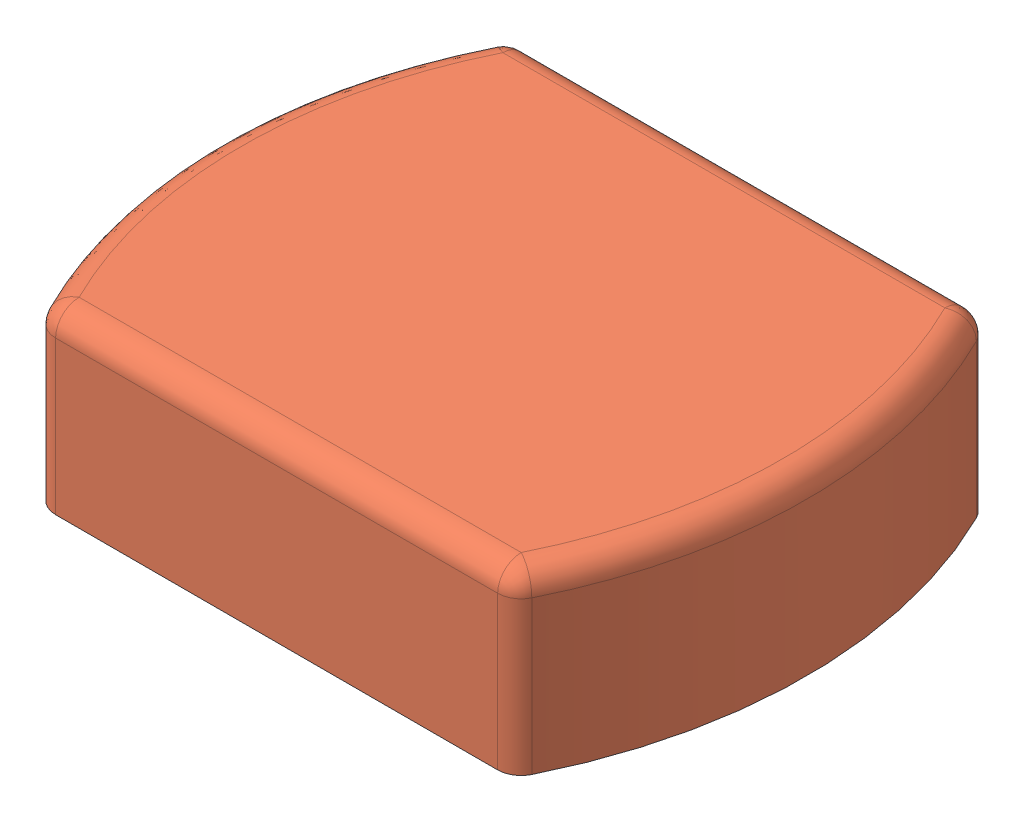
SolidWorks assembly Robot, configuration Default. Lengths in mm.
Overall size (63.5 21.87 50.8).
15 component instances, 9 part files, 28 mates.
Components (placement in the parent):
- Frame-1: Frame [Default] at origin size (45.72 11.65 40.64)
- Shell-1: Shell [Default] at (0 -11.049 0) size (63.5 19.05 50.8)
- PCB-1: PCB [Default] at (0 -5.588 0) size (45.72 1.52 40.64)
- BGM111-1: BGM111 [Default] at (-15.36 -6.75 0) x (1 0 0) z (0 0 -1) size (15 2 12.9)
- Stepper Motor-2: Stepper Motor [Default] at (7.6033 -3.826 -7.438) x (0 0 -1) z (1 0 0) size (12.5 9 8)
- 4-40 Screw-1: 4-40 Screw [92220A122] at (-20.32 -1.5875 17.78) x (0 1 0) z (0 0 1) size (11.33 4.65 4.65)
- 4-40 Screw-2: 4-40 Screw [92220A122] at (20.32 -1.5875 17.78) x (0 1 0) z (0 0 1) size (11.33 4.65 4.65)
- 4-40 Screw-3: 4-40 Screw [92220A122] at (20.32 -1.5875 -17.78) x (0 1 0) z (0 0 1) size (11.33 4.65 4.65)
- 4-40 Screw-4: 4-40 Screw [92220A122] at (-20.32 -1.5875 -17.78) x (0 1 0) z (0 0 1) size (11.33 4.65 4.65)
- Small Gear-1: Small Gear [2662N27] at (7.6033 0.174 -15.438) x (0.958969 -0.283511 0) z (0 0 1) size (6.87 6.87 3.01)
- Large Gear-1: Large Gear [2662N28] at (0 -4.826 -12.438) x (-0.58701 0.80958 0) z (0 0 -1) size (12.96 12.96 7.01)
- Stepper Motor-3: Stepper Motor [Default] at (7.6033 -3.826 7.438) x (0 0 1) z (-1 0 0) size (12.5 9 8)
- Small Gear-2: Small Gear [2662N27] at (7.6033 0.174 12.438) x (0.958969 -0.283511 0) z (0 0 1) size (6.87 6.87 3.01)
- Large Gear-2: Large Gear [2662N28] at (0 -4.826 12.438) x (0.58701 -0.80958 0) z (0 0 1) size (12.96 12.96 7.01)
- Wheel-2: Wheel [Default] at (0 -4.826 -16.438) x (-0.999664 -0.025912 0) z (0 0 -1) size (16.51 16.51 4)
Mates (geometry in assembly coordinates):
- Coincident5: coincident: plane of PCB-1 through (0 -6.35 0) normal (0 -1 0); plane of BGM111-1 through (-15.36 -6.35 0) normal (0 1 0)
- Coincident6: coincident: plane of PCB-1 through (-22.86 -4.826 -20.32) normal (-1 0 0); plane of BGM111-1 through (-22.86 -7.15 6.45) normal (-1 0 0)
- Width1: width: plane of PCB-1 through (-22.86 -4.826 20.32) normal (0 0 1); plane of PCB-1 through (-22.86 -4.826 -20.32) normal (0 0 -1); plane of BGM111-1 through (-22.86 -7.15 -6.45) normal (0 0 -1); plane of BGM111-1 through (-22.86 -7.15 6.45) normal (0 0 1)
- Width2: width: plane of Shell-1 through (-22.86 69.1723 -20.32) normal (0 0 1); plane of Shell-1 through (-22.86 69.1723 20.32) normal (0 0 -1); plane of PCB-1 through (-22.86 -4.826 -20.32) normal (0 0 -1); plane of PCB-1 through (-22.86 -4.826 20.32) normal (0 0 1)
- Width3: width: plane of Shell-1 through (-22.86 69.1723 20.32) normal (1 0 0); plane of Shell-1 through (22.86 69.1723 20.32) normal (-1 0 0); plane of PCB-1 through (-22.86 -4.826 -20.32) normal (-1 0 0); plane of PCB-1 through (22.86 -4.826 -20.32) normal (1 0 0)
- Coincident8: coincident: plane of PCB-1 through (0 -4.826 0) normal (0 1 0); plane of Stepper Motor-2 through (7.6033 -4.826 -7.438) normal (0 -1 0)
- Coincident10: coincident: plane of PCB-1 through (0 -6.35 0) normal (0 -1 0); plane of 4-40 Screw-1 through (-22.6441 -6.35 17.78) normal (0 1 0)
- Concentric1: concentric: cylinder of PCB-1 through (-20.32 -4.826 17.78) axis (0 1 0) radius 1.4732; cylinder of 4-40 Screw-1 through (-20.32 -6.35 17.78) axis (0 1 0) radius 2.3241
- Concentric2: concentric: cylinder of PCB-1 through (20.32 -4.826 17.78) axis (0 1 0) radius 1.4732; cylinder of 4-40 Screw-2 through (20.32 -6.35 17.78) axis (0 1 0) radius 2.3241
- Concentric3: concentric: cylinder of PCB-1 through (20.32 -4.826 -17.78) axis (0 1 0) radius 1.4732; cylinder of 4-40 Screw-3 through (20.32 -6.35 -17.78) axis (0 1 0) radius 2.3241
- Concentric4: concentric: cylinder of PCB-1 through (-20.32 -4.826 -17.78) axis (0 1 0) radius 1.4732; cylinder of 4-40 Screw-4 through (-20.32 -6.35 -17.78) axis (0 1 0) radius 2.3241
- Coincident11: coincident: plane of PCB-1 through (0 -6.35 0) normal (0 -1 0); plane of 4-40 Screw-4 through (-22.6441 -6.35 -17.78) normal (0 1 0)
- Coincident12: coincident: plane of PCB-1 through (0 -6.35 0) normal (0 -1 0); plane of 4-40 Screw-2 through (17.9959 -6.35 17.78) normal (0 1 0)
- Coincident13: coincident: plane of PCB-1 through (0 -6.35 0) normal (0 -1 0); plane of 4-40 Screw-3 through (17.9959 -6.35 -17.78) normal (0 1 0)
- Coincident14: coincident: plane of PCB-1 through (0 -4.826 0) normal (0 1 0); plane of Frame-1 through (0 -4.826 0) normal (0 -1 0)
- Width4: width: plane of Shell-1 through (-22.86 69.1723 20.32) normal (1 0 0); plane of Shell-1 through (22.86 69.1723 20.32) normal (-1 0 0); plane of Frame-1 through (-22.86 4.826 -20.32) normal (-1 0 0); plane of Frame-1 through (22.86 4.826 -20.32) normal (1 0 0)
- Width5: width: plane of Shell-1 through (-22.86 69.1723 -20.32) normal (0 0 1); plane of Shell-1 through (-22.86 69.1723 20.32) normal (0 0 -1); plane of Frame-1 through (-22.86 4.826 -20.32) normal (0 0 -1); plane of Frame-1 through (-22.86 4.826 20.32) normal (0 0 1)
- Coincident15: coordinate: point of Frame-1; point of assembly
- LimitDistance1: limit distance = 0 mm: plane of Frame-1 through (0 4.826 0) normal (0 1 0); plane of Shell-1 through (0 4.826 0) normal (0 -1 0)
- Concentric8: concentric: cylinder of Stepper Motor-2 through (7.6033 0.174 -12.938) axis (0 0 -1) radius 1.35; cylinder of Small Gear-1 through (7.6033 0.174 -15.4433) axis (0 0 1) radius 1.39
- Coincident23: coincident: plane of Stepper Motor-2 through (7.6033 0.174 -15.438) normal (0 0 -1); plane of Small Gear-1 through (8.5956 3.5304 -15.438) normal (0 0 -1)
- Concentric9: concentric: cylinder of Frame-1 through (0 -4.826 -19.438) axis (0 0 1) radius 2; cylinder of Large Gear-1 through (0 -4.826 -15.438) axis (0 0 1) radius 2
- Coincident26: coincident: plane of Frame-1 through (0 -4.826 -19.438) normal (0 0 -1); plane of Large Gear-1 through (1.6192 -3.652 -19.438) normal (0 0 -1)
- Coincident27: coincident: plane of Small Gear-1 through (8.2412 2.3317 -12.438) normal (0 0 1); plane of Large Gear-1 through (5.2623 -1.0104 -12.438) normal (0 0 1)
- Width6: width: plane of Frame-1 through (12.6833 4.826 -2.54) normal (-1 0 0); plane of Frame-1 through (2.5233 -4.826 -2.54) normal (1 0 0); plane of Stepper Motor-2 through (10.4783 -4.826 -6.788) normal (1 0 0); plane of Stepper Motor-2 through (4.7283 -4.826 -6.788) normal (-1 0 0)
- GearMate1: gear = 609.6 : 304.8 mm: cylinder of Small Gear-1 through (7.6033 0.174 -15.4433) axis (0 0 1) radius 1.39; cylinder of Large Gear-1 through (0 -4.826 -15.438) axis (0 0 1) radius 2
- Concentric13: concentric: cylinder of Large Gear-1 through (0 -4.826 -15.438) axis (0 0 1) radius 4; cylinder of Wheel-2 through (0 -4.826 -19.438) axis (0 0 1) radius 4
- Coincident28: coincident: plane of Large Gear-1 through (3.2383 -2.478 -15.438) normal (0 0 -1); plane of Wheel-2 through (0 -4.826 -15.438) normal (0 0 1)
